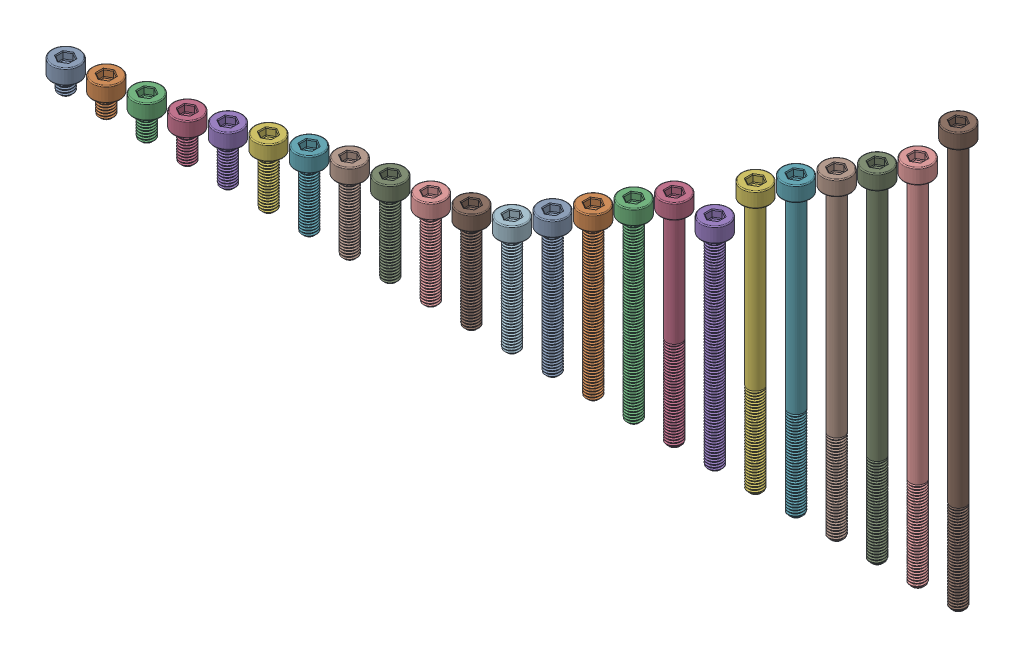
SolidWorks assembly M3, configuration Default. Lengths in mm.
Overall size (181.5 83.17 5.5).
23 component instances, 23 part files, 0 mates.
Components (placement in the parent):
- Screw_DIN_912_M3x3F_A2-1: Screw_DIN_912_M3x3F_A2 [Default] at origin size (5.5 6 5.5)
- Screw_DIN_912_M3x4F_A2-1: Screw_DIN_912_M3x4F_A2 [Default] at (8 0 0) size (5.5 7 5.5)
- Screw_DIN_912_M3x5F_A2-1: Screw_DIN_912_M3x5F_A2 [Default] at (16 0 0) size (5.5 8 5.5)
- Screw_DIN_912_M3x6F_A2-1: Screw_DIN_912_M3x6F_A2 [Default] at (24 0 0) size (5.5 9 5.5)
- Screw_DIN_912_M3x8F_A2-1: Screw_DIN_912_M3x8F_A2 [Default] at (32 0 0) size (5.5 11 5.5)
- Screw_DIN_912_M3x10F_A2-1: Screw_DIN_912_M3x10F_A2 [Default] at (40 0 0) size (5.5 13 5.5)
- Screw_DIN_912_M3x12F_A2-1: Screw_DIN_912_M3x12F_A2 [Default] at (48 0 0) size (5.5 15 5.5)
- Screw_DIN_912_M3x14F_A2-1: Screw_DIN_912_M3x14F_A2 [Default] at (56 0 0) size (5.5 17.01 5.5)
- Screw_DIN_912_M3x15F_A2-1: Screw_DIN_912_M3x15F_A2 [Default] at (64 0 0) size (5.5 18.02 5.5)
- Screw_DIN_912_M3x16F_A2-1: Screw_DIN_912_M3x16F_A2 [Default] at (72 0 0) size (5.5 19.02 5.5)
- Screw_DIN_912_M3x18F_A2-1: Screw_DIN_912_M3x18F_A2 [Default] at (80 0 0) size (5.5 21.03 5.5)
- Screw_DIN_912_M3x20F_A2-1: Screw_DIN_912_M3x20F_A2 [Default] at (88 0 0) size (5.5 23.04 5.5)
- Screw_DIN_912_M3x25F_A2-1: Screw_DIN_912_M3x25F_A2 [Default] at (96 0 0) size (5.5 28.08 5.5)
- Screw_DIN_912_M3x30F_A2-1: Screw_DIN_912_M3x30F_A2 [Default] at (104 0 0) size (5.5 33.11 5.5)
- Screw_DIN_912_M3x35F_A2-1: Screw_DIN_912_M3x35F_A2 [Default] at (112 0 0) size (5.5 38.13 5.5)
- Screw_DIN_912_M3x40_A2-1: Screw_DIN_912_M3x40_A2 [Default] at (120 0 0) size (5.5 43 5.5)
- Screw_DIN_912_M3x40F_A2-1: Screw_DIN_912_M3x40F_A2 [Default] at (128 0 0) size (5.5 43.17 5.5)
- Screw_DIN_912_M3x50_A2-1: Screw_DIN_912_M3x50_A2 [Default] at (136 0 0) size (5.5 53 5.5)
- Screw_DIN_912_M3x55_A2-1: Screw_DIN_912_M3x55_A2 [Default] at (144 0 0) size (5.5 58 5.5)
- Screw_DIN_912_M3x60_A2-1: Screw_DIN_912_M3x60_A2 [Default] at (152 0 0) size (5.5 63 5.5)
- Screw_DIN_912_M3x65_A2-1: Screw_DIN_912_M3x65_A2 [Default] at (160 0 0) size (5.5 68 5.5)
- Screw_DIN_912_M3x70_A2-1: Screw_DIN_912_M3x70_A2 [Default] at (168 0 0) size (5.5 73 5.5)
- Screw_DIN_912_M3x80_A2-1: Screw_DIN_912_M3x80_A2 [Default] at (176 0 0) size (5.5 83 5.5)
